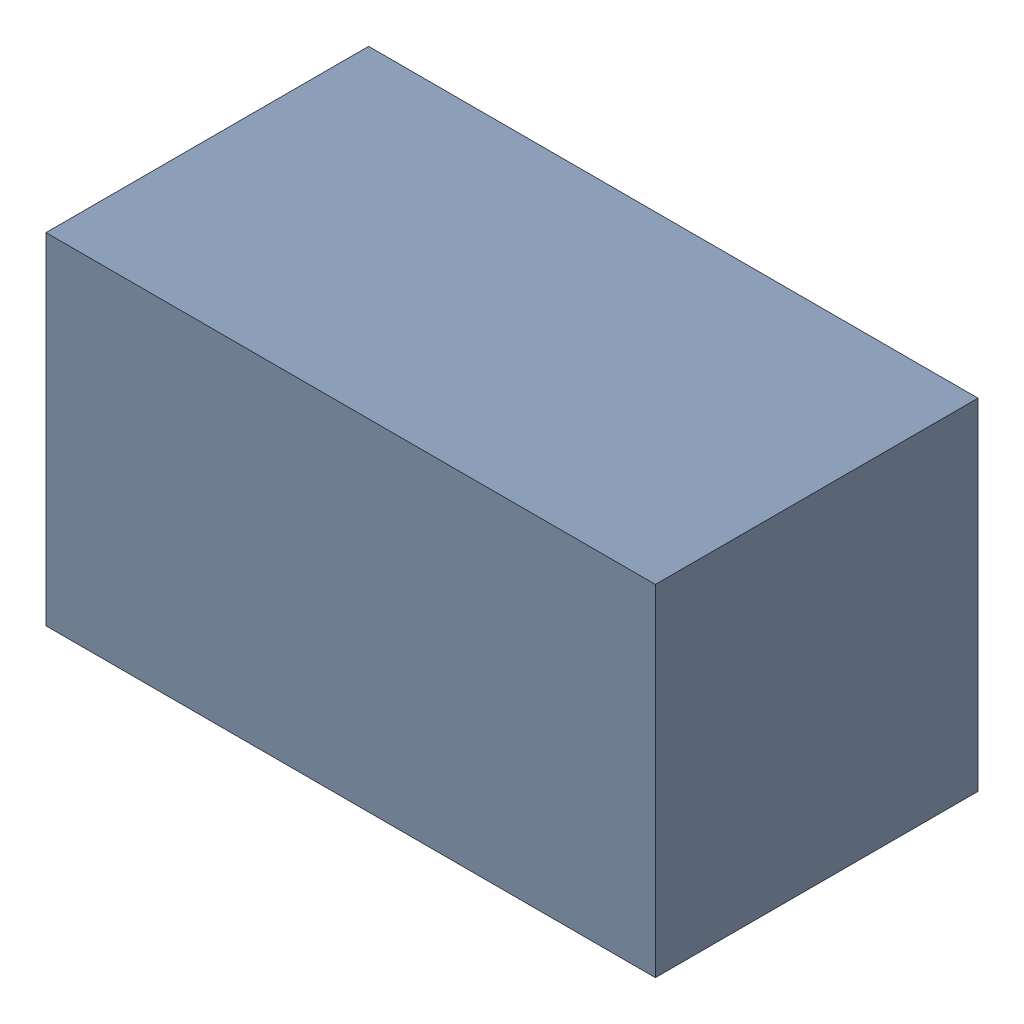
SolidWorks assembly R4, configuration Default. Lengths in mm.
Overall size (1.7 0.95 0.9).
2 component instances, 1 part files, 0 mates.
Components (placement in the parent):
- 4438510848-1: 4438510848 [Default] at (19.443 13.716 0) size (1.7 0.95 0.9)
  - Extruded_3-1: Extruded_3 [Default] at origin size (1.7 0.95 0.9)
